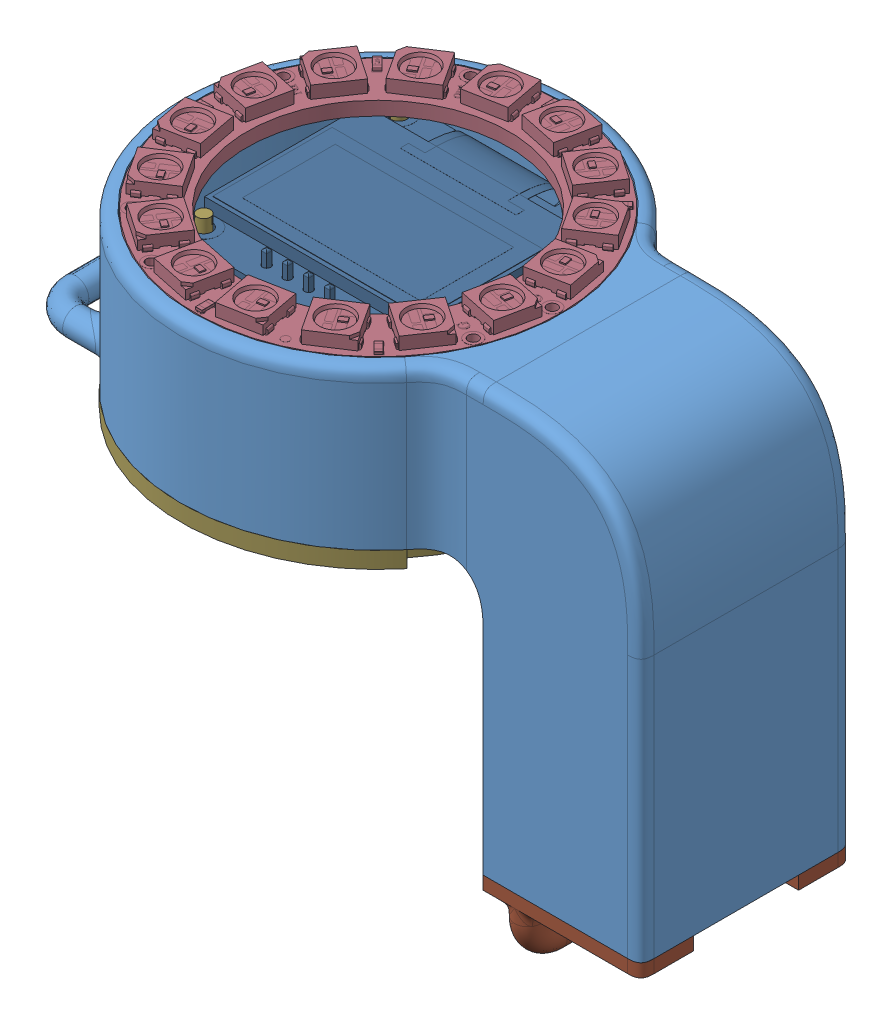
SolidWorks assembly Complete Assembly, configuration Default. Lengths in mm.
Overall size (75.09 60.44 61.18).
23 component instances, 14 part files, 13 mates.
Components (placement in the parent):
- Base Structure-1: Base Structure [Default] at (-142.2824 -45.9767 99.4264) size (73.08 51.16 48.37)
- MPU 6050 IMU-1: MPU 6050 IMU [Default] at (-135.0335 -23.8148 80.6298) x (-1 0 0) z (0 0 1) size (21.11 11.22 19.63)
  - Base-1: Base [Default] at (7.2489 10.9584 16.5726) size (21.11 1.14 15.75)
  - sensor chip-1: sensor chip [Default] at (7.2489 11.5499 17.4466) size (5.4 0.9 5.4)
  - S2NH chip-1: S2NH chip [Default] at (16.1026 12.3799 16.5726) size (3 1.35 3.65)
  - Resistor small-3: Resistor small [Default] at (16.1026 11.5314 19.3726) size (2.75 0.99 1)
  - Resistor small-4: Resistor small [Default] at (13.9776 11.5314 15.6976) x (0 0 -1) z (1 0 0) size (2.75 0.99 1)
  - Resistor small black-3: Resistor small black [Default] at (12.6276 11.5299 15.6976) x (0 0 1) z (-1 0 0) size (2.45 0.6 1.02)
  - Resistor small black-4: Resistor small black [Default] at (11.1276 11.5299 15.6976) x (0 0 1) z (-1 0 0) size (2.45 0.6 1.02)
  - Resistor small-5: Resistor small [Default] at (12.6276 11.5314 19.3216) x (0 0 -1) z (1 0 0) size (2.75 0.99 1)
  - Resistor small-6: Resistor small [Default] at (11.1276 11.5314 19.3216) x (0 0 -1) z (1 0 0) size (2.75 0.99 1)
  - Resistor small-7: Resistor small [Default] at (3.3702 11.5314 19.3216) x (0 0 -1) z (1 0 0) size (2.75 0.99 1)
  - Resistor small black-5: Resistor small black [Default] at (1.8702 11.5299 15.6972) x (0 0 -1) z (1 0 0) size (2.45 0.6 1.02)
  - Resistor small-8: Resistor small [Default] at (3.3702 11.5314 15.6976) x (0 0 1) z (-1 0 0) size (2.75 0.99 1)
  - Small LED-1: Small LED [Default] at (0.3652 11.5299 15.6976) size (0.85 0.84 1.9)
  - Resistor small black-6: Resistor small black [Default] at (1.8702 11.5299 19.3216) x (0 0 1) z (-1 0 0) size (2.45 0.6 1.02)
  - Resistor black-1: Resistor black [Default] at (7.2489 12.3799 21.6466) size (4.2 1.6 1.6)
  - Pin Header 1x8 TH Angle Pitch 2.54mm.stp-1: Pin Header 1x8 TH Angle Pitch 2.54mm.stp [Default] at (-1.7551 15.6761 8.0216) x (0.999997 -0.0026 0) z (0 0 1) size (20.33 11.16 6.3)
- User Library-128x64I2COLEDDisplayAdafruit-1: User Library-128x64I2COLEDDisplayAdafruit [Default] at (-176.6128 -29.7817 101.8704) x (-1 0 0) z (0 1 0) size (26.7 28.02 10.92)
- Bottom Cap-1: Bottom Cap [Default] at (-99.4199 -77.7267 88.3139) x (-1 0 0) z (0 0 -1) size (19.1 9.57 25.5)
- BaseCap-1: BaseCap [Default] at (-142.2824 -47.9767 99.4264) x (0 0 -1) z (1 0 0) size (47.62 19.4 46.04)
- NeoPixel16x-1: NeoPixel16x [Default] at (-142.2824 -28.5767 99.4264) x (-0.837169 0 -0.546944) z (0 1 0) size (44.2 44.2 3.36)
- arduino nano-1: arduino nano [Default] at (-106.7949 -36.7592 107.0464) x (0 -1 0) z (0 0 1) size (45 13.85 18)
Mates (geometry in assembly coordinates):
- Parallel2: parallel: plane of Base Structure-1 through (-166.0969 -45.9767 112.1264) normal (0 0 1); plane of User Library-128x64I2COLEDDisplayAdafruit-1 through (-155.5324 -30.0267 107.1264) normal (0 0 1)
- Distance2: distance = 3.175 mm: plane of MPU 6050 IMU-1/Base-1 through (-142.2824 -34.2017 97.2024) normal (0 1 0); plane of User Library-128x64I2COLEDDisplayAdafruit-1 through (-142.2824 -31.0267 98.8664) normal (0 -1 0)
- Distance3: distance = 6.35 mm: plane of MPU 6050 IMU-1/Base-1 through (-131.7287 -35.3447 105.0764) normal (0 0 1); plane of User Library-128x64I2COLEDDisplayAdafruit-1 through (-155.6324 -31.0267 111.4264) normal (0 0 1)
- Width2: width: plane of MPU 6050 IMU-1/Base-1 through (-152.8361 -35.3447 105.0764) normal (-1 0 0); plane of MPU 6050 IMU-1/Base-1 through (-131.7287 -35.3447 105.0764) normal (1 0 0); plane of User Library-128x64I2COLEDDisplayAdafruit-1 through (-128.9324 -31.0267 83.5664) normal (1 0 0); plane of User Library-128x64I2COLEDDisplayAdafruit-1 through (-155.6324 -31.0267 83.5664) normal (-1 0 0)
- Coincident13: coincident: plane of Base Structure-1 through (-97.8324 -77.7267 112.1264) normal (0 -1 0); plane of Bottom Cap-1 through (-99.4199 -77.7267 88.3139) normal (0 1 0)
- Coincident17: coincident: plane of Base Structure-1 through (-116.8824 -45.9767 99.4264) normal (-1 0 0); plane of Bottom Cap-1 through (-116.8824 -79.3142 112.1264) normal (-1 0 0)
- Coincident18: coincident: plane of Base Structure-1 through (-166.0969 -45.9767 112.1264) normal (0 0 1); plane of Bottom Cap-1 through (-97.8324 -79.3142 112.1264) normal (0 0 1)
- Concentric4: concentric: cylinder of Base Structure-1 through (-142.2824 -26.9267 99.4264) axis (0 -1 0) radius 23.8125; cylinder of BaseCap-1 through (-142.2824 -45.9767 99.4264) axis (0 -1 0) radius 23.8125
- Coincident19: coincident: plane of Base Structure-1 through (-142.2824 -45.9767 99.4264) normal (0 -1 0); plane of BaseCap-1 through (-142.2824 -45.9767 99.4264) normal (0 1 0)
- Concentric5: concentric: cylinder of Base Structure-1 through (-142.2824 -45.9767 99.4264) axis (0 1 0) radius 22.225; cylinder of NeoPixel16x-1 through (-142.2824 -28.5767 99.4264) axis (0 1 0) radius 22.1
- Coincident20: coincident: plane of Base Structure-1 through (-142.2824 -26.9267 99.4264) normal (0 1 0); plane of NeoPixel16x-1 through (-142.2824 -26.9267 99.4264) normal (0 1 0)
- Width3: width: plane of arduino nano-1 through (-105.1949 -32.9392 108.4264) normal (0 0 1); plane of arduino nano-1 through (-105.1949 -32.9392 90.4264) normal (0 0 -1); plane of Base Structure-1 through (-166.0969 -45.9767 112.1264) normal (0 0 1); plane of Base Structure-1 through (-166.0969 -45.9767 86.7264) normal (0 0 -1)
- Coincident21: coincident: plane of Bottom Cap-1 through (-99.4199 -76.1392 88.3139) normal (0 1 0); plane of arduino nano-1 through (-105.1949 -76.1392 90.4264) normal (0 -1 0)
